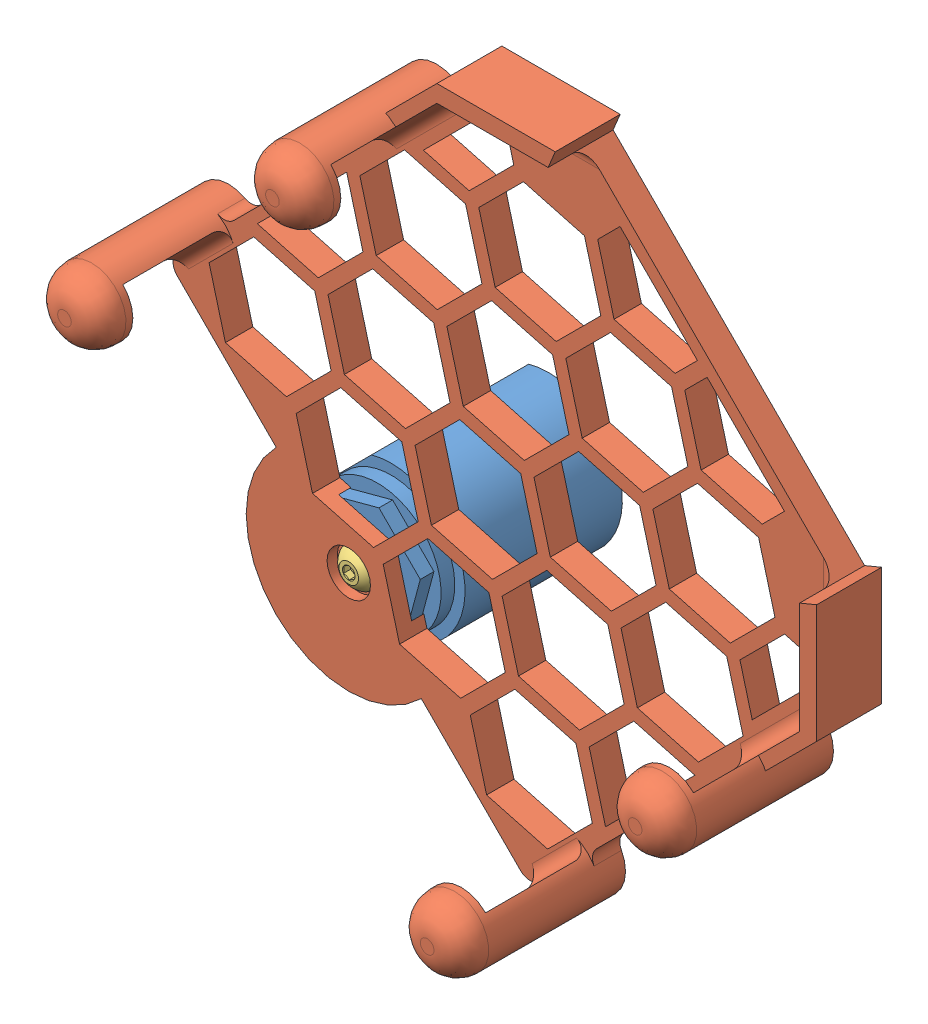
SolidWorks assembly Cat S60 Suction Cup Phone Mount Assembly, configuration Default. Lengths in mm.
Overall size (125.51 125.51 49.2).
4 component instances, 4 part files, 8 mates.
Components (placement in the parent):
- CAT S60 Phone Suction Mount-Adapter-1: CAT S60 Phone Suction Mount-Adapter [Default] at (5.7822 25.9301 -5.8575) x (0.707107 0.707107 0) z (0 0 1) size (21.6 20.2 27)
- CAT S60 Car Holder-Suction Mount-1: CAT S60 Car Holder-Suction Mount [Default] at (85.3317 52.4466 19.3425) x (-0.707107 0.707107 0) z (0 0 1) size (85 92.5 24)
- 92949A108_18-8 SS BUTTON-HEAD SOCKET CAP SCREW-1: 92949A108_18-8 SS BUTTON-HEAD SOCKET CAP SCREW [92949A108] at (5.7822 25.9301 23.3425) size (5.41 5.41 11.35)
- 91831A005_TYPE 18-8 STAINLESS STL NYLON-INSERT LOCKNUT-1: 91831A005_TYPE 18-8 STAINLESS STL NYLON-INSERT LOCKNUT [91831A005] at (5.7822 25.9301 16.7425) x (0.965926 -0.258819 0) z (0.258819 0.965926 0) size (6.35 3.66 7.33)
Mates (geometry in assembly coordinates):
- Concentric1: concentric aligned: circle of CAT S60 Phone Suction Mount-Adapter-1; circle of CAT S60 Car Holder-Suction Mount-1
- Coincident3: coincident anti-aligned: plane of CAT S60 Phone Suction Mount-Adapter-1 through (5.7822 25.9301 21.1425) normal (0 0 1); plane of CAT S60 Car Holder-Suction Mount-1 through (85.3317 52.4466 21.1425) normal (0 0 -1)
- Parallel4: parallel aligned: plane of CAT S60 Phone Suction Mount-Adapter-1 through (-4.625 28.8166 17.1425) normal (-0.707107 0.707107 0); plane of CAT S60 Car Holder-Suction Mount-1 through (32.2987 105.4797 23.3425) normal (-0.707107 0.707107 0)
- Coincident5: coincident anti-aligned: plane of CAT S60 Car Holder-Suction Mount-1 through (4.5609 27.1515 21.8439) normal (0 0 1); plane of 92949A108_18-8 SS BUTTON-HEAD SOCKET CAP SCREW-1 through (5.7822 23.225 21.8439) normal (0 0 -1)
- Concentric2: concentric anti-aligned: circle of CAT S60 Phone Suction Mount-Adapter-1; circle of 92949A108_18-8 SS BUTTON-HEAD SOCKET CAP SCREW-1
- Coincident9: coincident anti-aligned: plane of CAT S60 Phone Suction Mount-Adapter-1 through (5.7822 25.9301 16.7425) normal (0 0 -1); plane of 91831A005_TYPE 18-8 STAINLESS STL NYLON-INSERT LOCKNUT-1 through (8.3745 23.3378 16.7425) normal (0 0 1)
- Concentric3: concentric anti-aligned: circle of CAT S60 Phone Suction Mount-Adapter-1; circle of 91831A005_TYPE 18-8 STAINLESS STL NYLON-INSERT LOCKNUT-1
- Parallel5: parallel anti-aligned: plane of CAT S60 Phone Suction Mount-Adapter-1 through (4.781 22.1937 16.7425) normal (0.707107 0.707107 0); plane of 91831A005_TYPE 18-8 STAINLESS STL NYLON-INSERT LOCKNUT-1 through (4.8333 22.3889 13.1707) normal (-0.707107 -0.707107 0)
